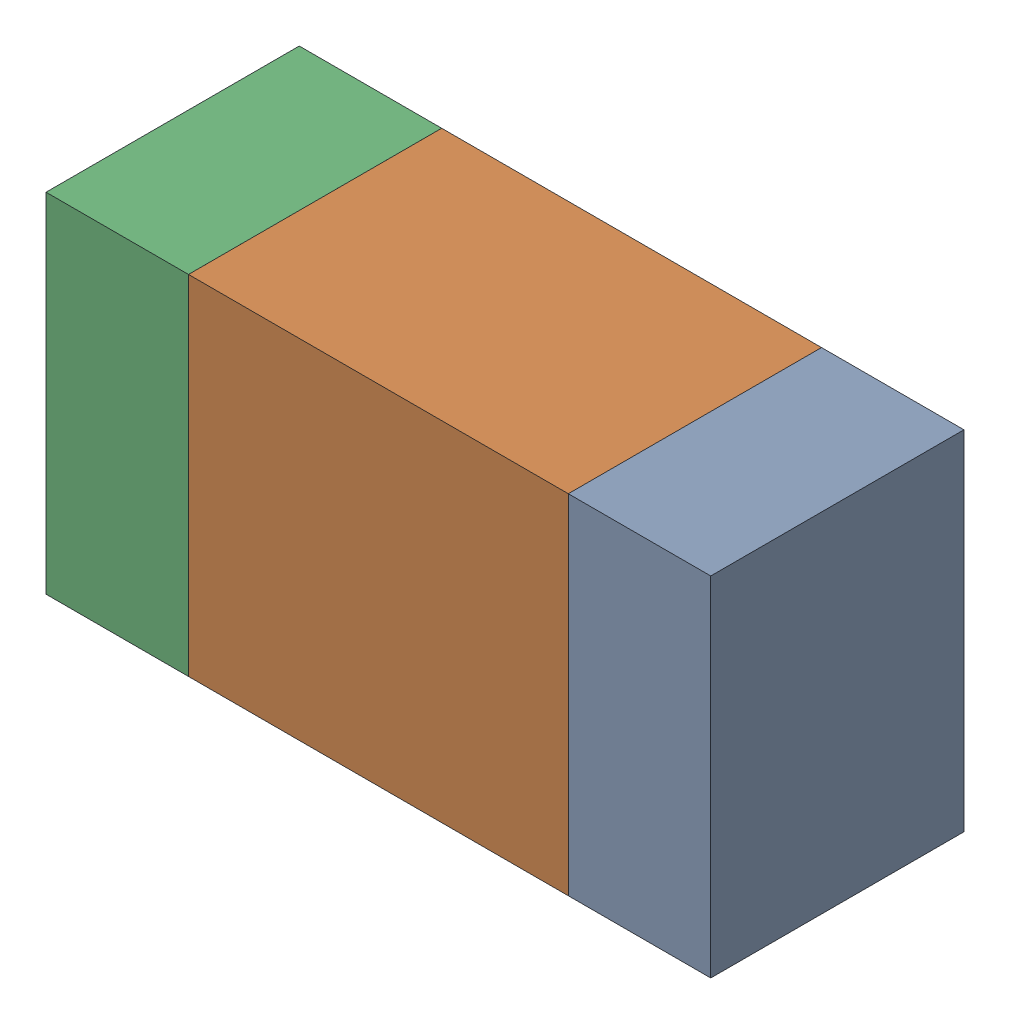
SolidWorks assembly R704PCB, configuration Default. Lengths in mm.
Overall size (1.05 0.55 0.4).
6 component instances, 2 part files, 0 mates.
Components (placement in the parent):
- 854785432-1: 854785432 [Default] at (104.4124 122.4001 -2.0638) size (0.22 0.55 0.4)
  - Extruded-1: Extruded [Default] at origin size (0.22 0.55 0.4)
- 854785568-1: 854785568 [Default] at (103.9999 122.4001 -2.0638) size (0.6 0.55 0.4)
  - Extruded_2-1: Extruded_2 [Default] at origin size (0.6 0.55 0.4)
- 854785432-2: 854785432 [Default] at (103.5874 122.4001 -2.0638) size (0.22 0.55 0.4)
  - Extruded-1: Extruded [Default] at origin size (0.22 0.55 0.4)
